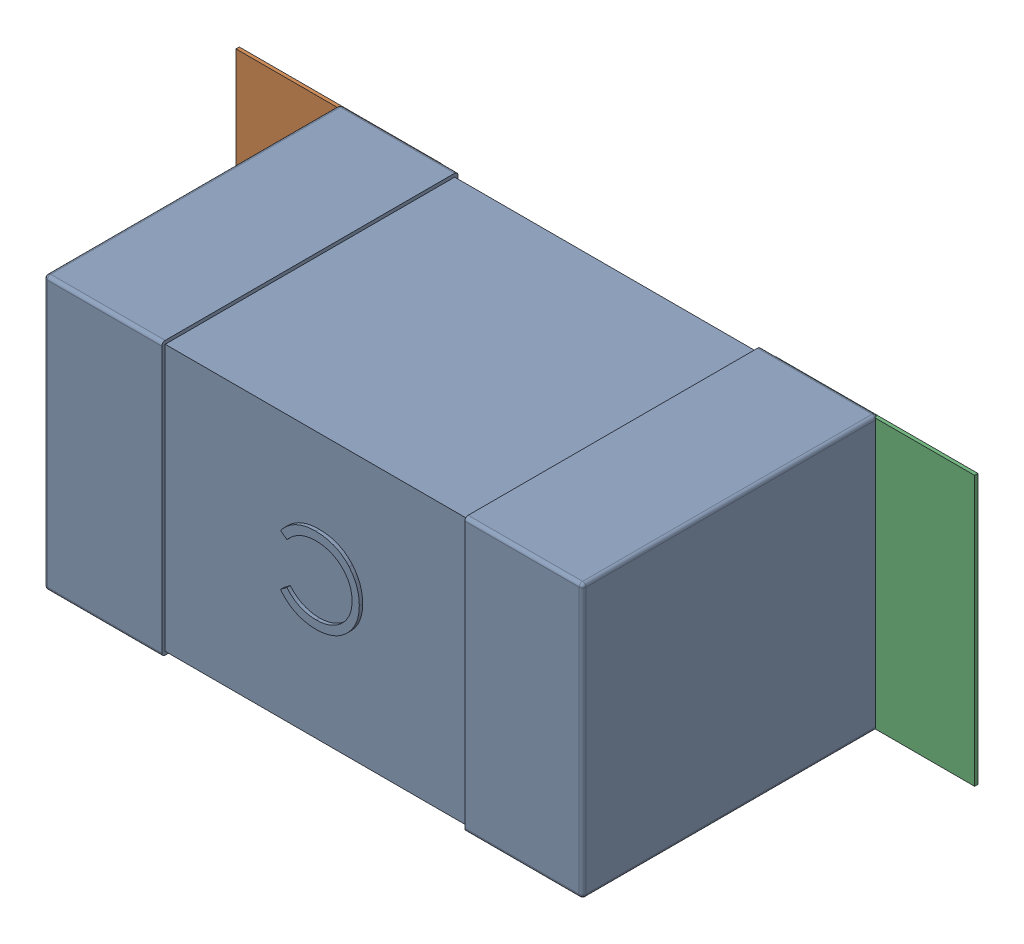
SolidWorks assembly C35, configuration Défaut. Lengths in mm.
Overall size (2.19 0.81 0.88).
5 component instances, 2 part files, 0 mates.
Components (placement in the parent):
- 0603_C-1: 0603_C [Défaut] at (6.2513 -10.3533 0) x (-1 0 0) z (0 0 1) size (1.6 0.81 0.88)
- 6634915696-1: 6634915696 [Défaut] at (5.0013 -10.3533 0) size (0.6 0.8 0.01)
  - Extruded_497-1: Extruded_497 [Défaut] at origin size (0.6 0.8 0.01)
- 6634915696-2: 6634915696 [Défaut] at (6.5962 -10.3533 0) size (0.6 0.8 0.01)
  - Extruded_497-1: Extruded_497 [Défaut] at origin size (0.6 0.8 0.01)
